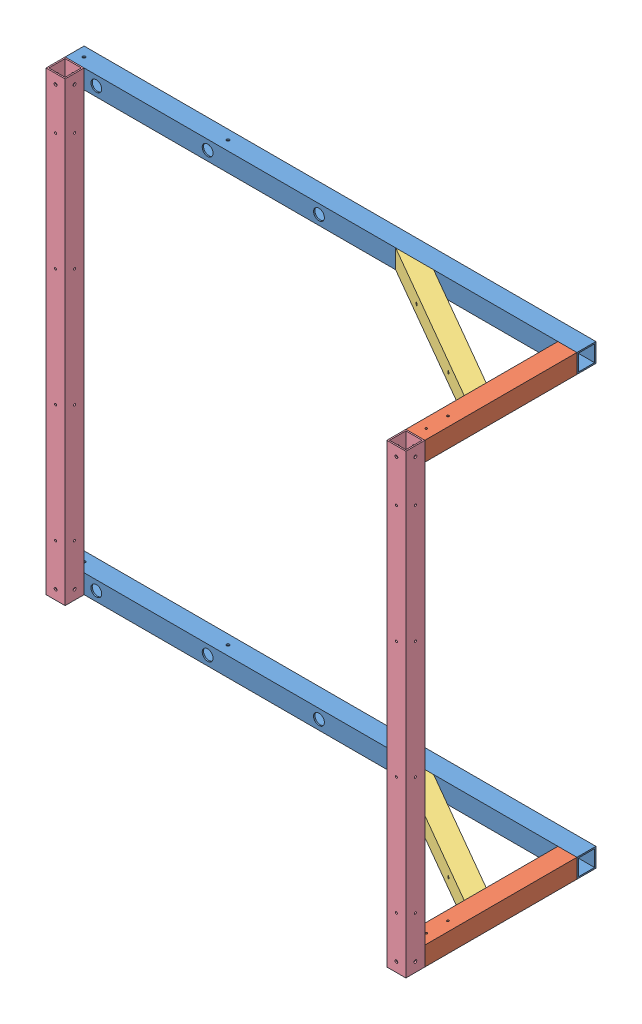
SolidWorks assembly GE-24103, configuration Default. Lengths in mm.
Overall size (1196.98 1066.8 444.5).
8 component instances, 4 part files, 17 mates.
Components (placement in the parent):
- GE-24103-01-1: GE-24103-01 [Default] at (-339.6849 664.7219 983.6318) x (1 0 0) z (0 0 -1) size (1196.97 44.45 44.45)
- GE-24103-03-1: GE-24103-03 [Default] at (857.2901 620.2719 1028.0818) x (0 0 1) z (0 -1 0) size (355.6 44.45 44.45)
- GE-24103-04-1: GE-24103-04 [Default] at (455.616 664.7219 989.5869) x (0.866025 0 0.5) z (0.5 0 -0.866025) size (438.15 44.45 44.45)
- GE-24103-01-2: GE-24103-01 [Default] at (-339.6849 1687.0719 983.6318) x (1 0 0) z (0 0 -1) size (1196.97 44.45 44.45)
- GE-24103-03-2: GE-24103-03 [Default] at (857.2901 1642.6219 1028.0818) x (0 0 1) z (0 -1 0) size (355.6 44.45 44.45)
- GE-24103-04-2: GE-24103-04 [Default] at (455.616 1687.0719 989.5869) x (0.866025 0 0.5) z (0.5 0 -0.866025) size (438.15 44.45 44.45)
- GE-24103-02-2: GE-24103-02 [Default] at (-339.6849 620.2719 1028.0818) x (0 1 0) z (0 0 -1) size (1066.8 44.45 44.45)
- GE-24103-02-3: GE-24103-02 [Default] at (857.2901 1687.0719 1383.6818) x (0 -1 0) z (0 0 -1) size (1066.8 44.45 44.45)
Mates (geometry in assembly coordinates):
- Coincident8: coincident aligned: plane of GE-24103-01-1 through (857.2901 664.7219 983.6318) normal (1 0 0); plane of GE-24103-03-1 through (857.2901 620.2719 1383.6818) normal (1 0 0)
- Coincident13: coincident aligned: plane of Weldment Angled-1 through (812.8401 664.7219 1247.1568) normal (-0.5 0 0.866025); plane of Weldment Angled-2 through (812.8401 1687.0719 1247.1568) normal (-0.5 0 0.866025)
- Coincident14: coincident aligned: plane of GE-24103-03-1 through (812.8401 620.2719 1383.6818) normal (-1 0 0); plane of GE-24103-03-2 through (812.8401 1642.6219 1383.6818) normal (-1 0 0)
- Coincident15: coincident aligned: plane of GE-24103-03-1 through (857.2901 620.2719 1383.6818) normal (0 0 1); plane of GE-24103-03-2 through (857.2901 1642.6219 1383.6818) normal (0 0 1)
- Coincident16: coincident aligned: plane of GE-24103-01-1 through (857.2901 664.7219 983.6318) normal (1 0 0); plane of GE-24103-01-2 through (857.2901 1687.0719 983.6318) normal (1 0 0)
- Coincident19: coincident aligned: plane of GE-24103-03-2 through (857.2901 1642.6219 1383.6818) normal (0 -1 0); plane of Weldment Angled-2 through (835.0651 1642.6219 1208.6619) normal (0 -1 0)
- Coincident20: coincident aligned: plane of GE-24103-03-1 through (857.2901 620.2719 1383.6818) normal (1 0 0); plane of GE-24103-02-3 through (857.2901 620.2719 1383.6818) normal (1 0 0)
- Coincident21: coincident anti-aligned: plane of GE-24103-03-1 through (857.2901 620.2719 1383.6818) normal (0 0 1); plane of GE-24103-02-3 through (857.2901 620.2719 1383.6818) normal (0 0 -1)
- Coincident22: coincident aligned: plane of GE-24103-03-1 through (857.2901 620.2719 1383.6818) normal (0 -1 0); plane of GE-24103-02-3 through (857.2901 620.2719 1383.6818) normal (0 -1 0)
- Coincident23: coincident aligned: plane of GE-24103-03-2 through (857.2901 1687.0719 1383.6818) normal (0 1 0); plane of GE-24103-02-3 through (857.2901 1687.0719 1383.6818) normal (0 1 0)
- Coincident30: coincident aligned: plane of GE-24103-01-2 through (-339.6849 1687.0719 983.6318) normal (-1 0 0); plane of GE-24103-02-2 through (-339.6849 1687.0719 1028.0818) normal (-1 0 0)
- Coincident39: coincident anti-aligned: plane of GE-24103-01-2 through (857.2901 1687.0719 1028.0818) normal (0 0 1); plane of GE-24103-02-2 through (-339.6849 1687.0719 1028.0818) normal (0 0 -1)
- Coincident40: coincident anti-aligned: plane of GE-24103-01-2 through (857.2901 1687.0719 1028.0818) normal (0 0 1); plane of GE-24103-03-2 through (857.2901 1642.6219 1028.0818) normal (0 0 -1)
- Coincident41: coincident aligned: plane of GE-24103-01-2 through (857.2901 1642.6219 983.6318) normal (0 -1 0); plane of GE-24103-03-2 through (857.2901 1642.6219 1383.6818) normal (0 -1 0)
- Coincident42: coincident aligned: plane of GE-24103-01-2 through (857.2901 1687.0719 983.6318) normal (0 1 0); plane of GE-24103-02-2 through (-339.6849 1687.0719 1028.0818) normal (0 1 0)
- Coincident45: coincident aligned: plane of GE-24103-01-1 through (857.2901 620.2719 983.6318) normal (0 -1 0); plane of GE-24103-03-1 through (857.2901 620.2719 1383.6818) normal (0 -1 0)
- Coincident47: coincident aligned: plane of GE-24103-01-1 through (857.2901 620.2719 983.6318) normal (0 -1 0); plane of Weldment Angled-1 through (835.0651 620.2719 1208.6619) normal (0 -1 0)
